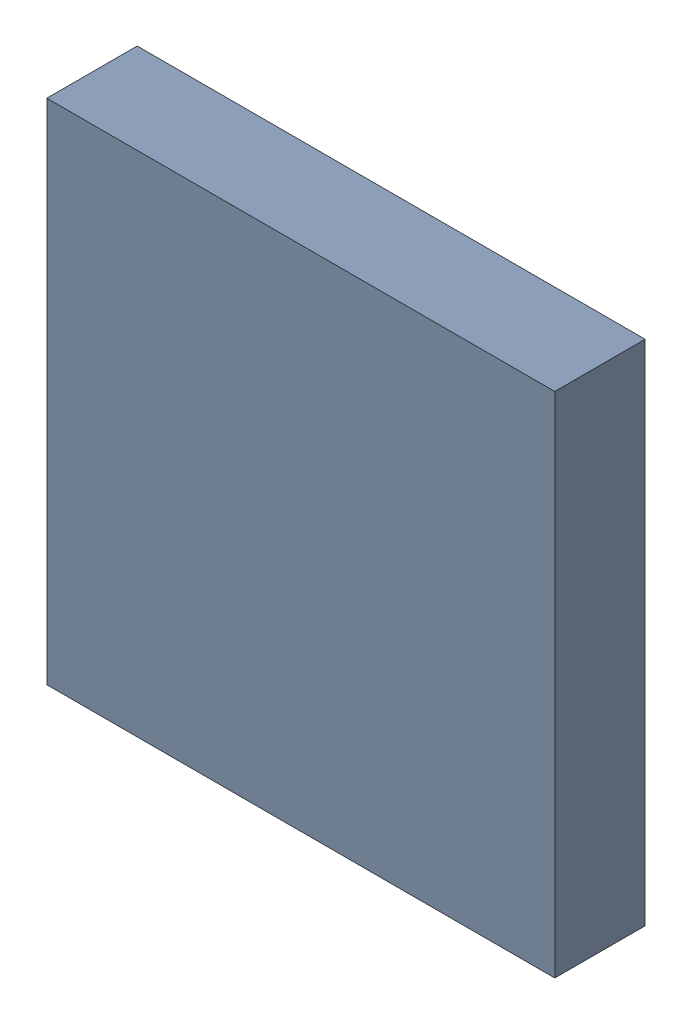
SolidWorks assembly U11, configuration Default. Lengths in mm.
Overall size (5 5 0.89).
2 component instances, 1 part files, 0 mates.
Components (placement in the parent):
- 804367824-1: 804367824 [Default] at (39.096 46.5884 -1.3115) size (5 5 0.89)
  - Extruded (5)-1: Extruded (5) [Default] at origin size (5 5 0.89)
